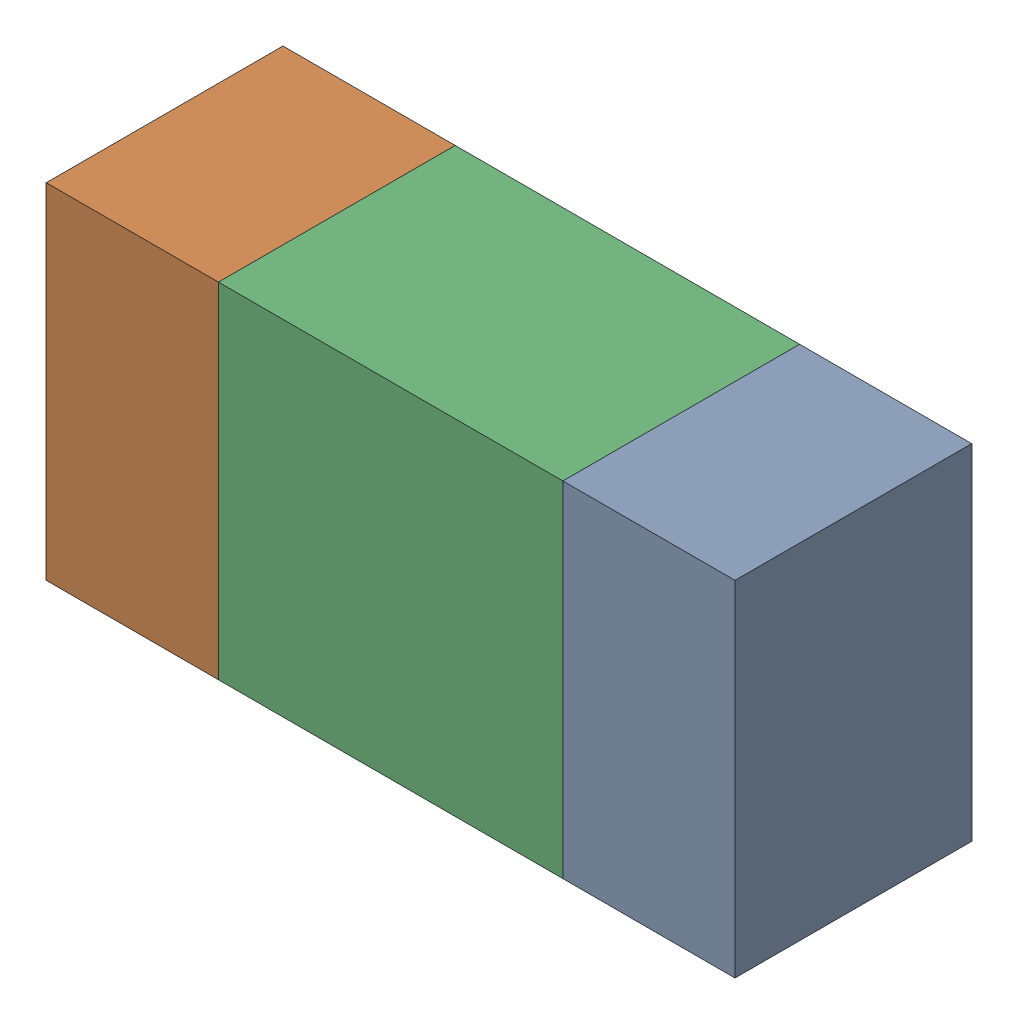
SolidWorks assembly R75, configuration ﾃﾞﾌｫﾙﾄ. Lengths in mm.
Overall size (1.6 0.8 0.55).
6 component instances, 2 part files, 0 mates.
Components (placement in the parent):
- 689261512-1: 689261512 [ﾃﾞﾌｫﾙﾄ] at (18.0999 49.9999 0) size (0.4 0.8 0.55)
  - Extruded_32-1: Extruded_32 [ﾃﾞﾌｫﾙﾄ] at origin size (0.4 0.8 0.55)
- 689261512-2: 689261512 [ﾃﾞﾌｫﾙﾄ] at (16.8999 49.9999 0) size (0.4 0.8 0.55)
  - Extruded_32-1: Extruded_32 [ﾃﾞﾌｫﾙﾄ] at origin size (0.4 0.8 0.55)
- 689261648-1: 689261648 [ﾃﾞﾌｫﾙﾄ] at (17.5 49.9999 0) size (0.8 0.8 0.55)
  - Extruded_33-1: Extruded_33 [ﾃﾞﾌｫﾙﾄ] at origin size (0.8 0.8 0.55)
